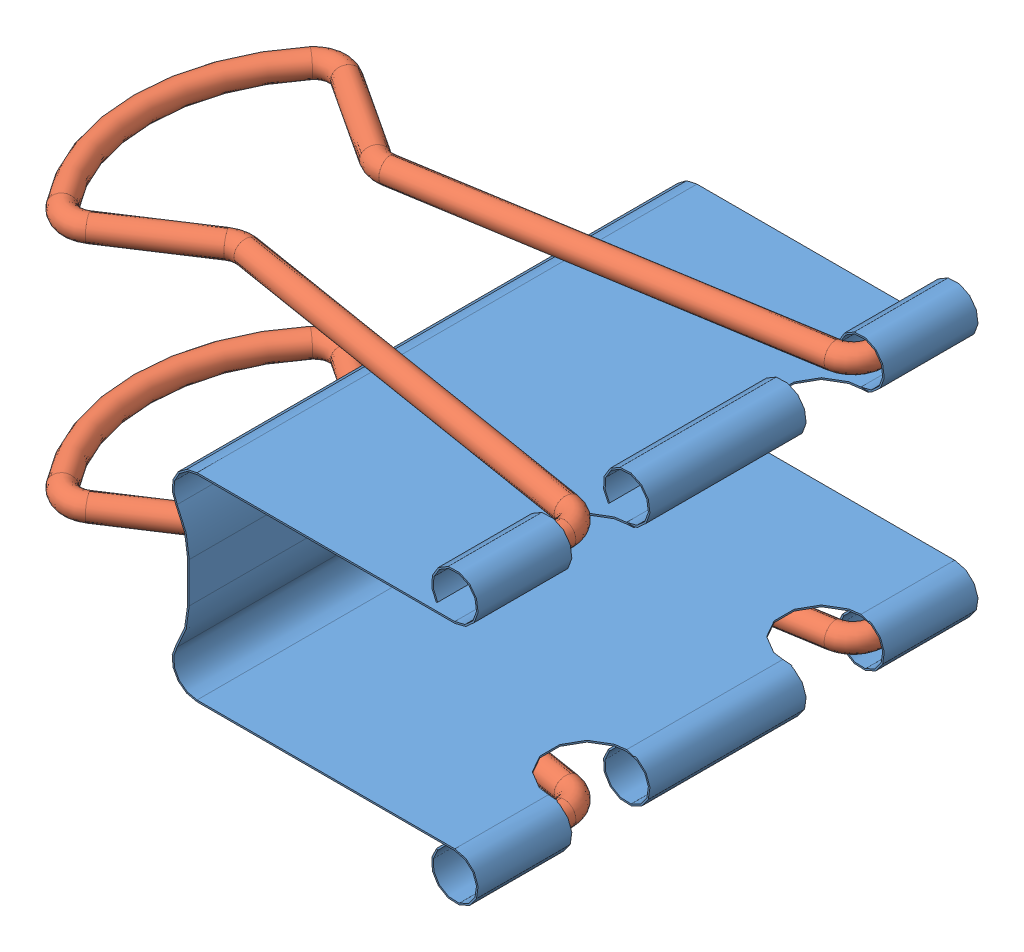
SolidWorks assembly BINDER CLIP, configuration Default. Lengths in mm.
Overall size (39.25 18.5 32).
3 component instances, 2 part files, 0 mates.
Components (placement in the parent):
- BINDER CLIP BODY-1: BINDER CLIP BODY [Default] at origin size (19.6 18.5 32)
- BINDER CLIP ARM-1: BINDER CLIP ARM [Default] at (-20 -7.75 -1) x (0 0 -1) z (0 -1 0) size (30 38.5 1.5)
- BINDER CLIP ARM-2: BINDER CLIP ARM [Default] at (-20 7.75 -1) x (0 0 1) z (0 1 0) size (30 38.5 1.5)
